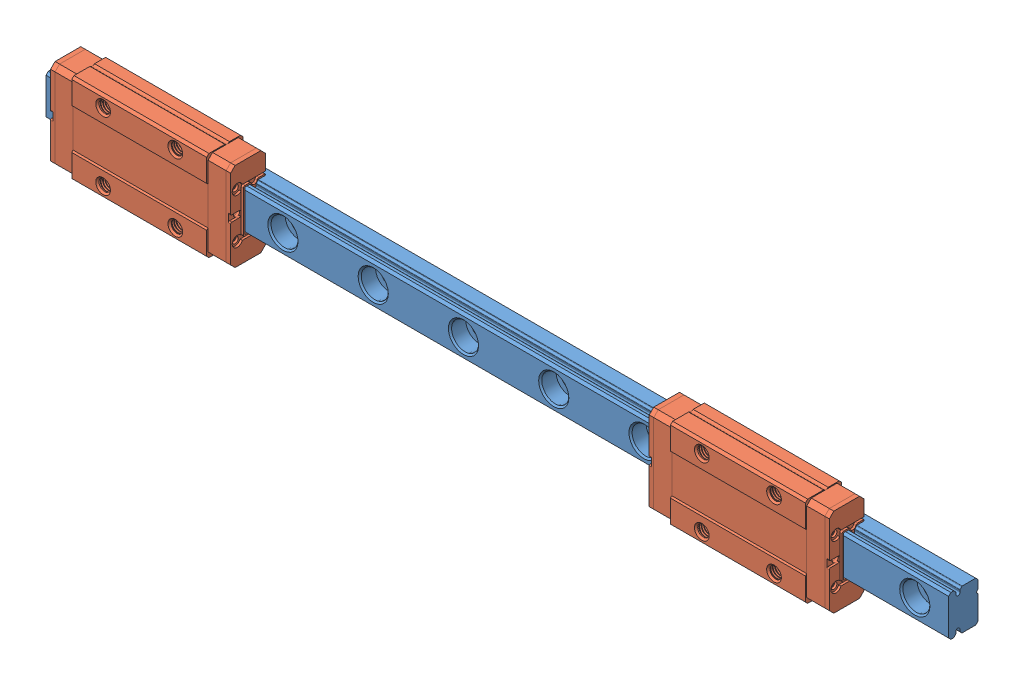
SolidWorks assembly HIWIN_MGN9H_together, configuration two_sliders. Lengths in mm.
Overall size (200 20 10.11).
3 component instances, 2 part files, 7 mates.
Components (placement in the parent):
- Schiene_HIWIN_MGN9H-1: Schiene_HIWIN_MGN9H [Standard] at origin
- slider_HIWIN_MGN9H-1: slider_HIWIN_MGN9H [Standard] at (256.8127 -14.5 1.96)
- slider_HIWIN_MGN9H-2: slider_HIWIN_MGN9H [Standard] at (124.1657 -14.5 1.96)
Mates (geometry in assembly coordinates):
- Deckungsgleich1: coordinate: point of Schiene_HIWIN_MGN9H-1
- Breite1: width anti-aligned: plane of Schiene_HIWIN_MGN9H-1 through (0 0 0.5) normal (0 1 0); plane of Schiene_HIWIN_MGN9H-1 through (0 -9 3.5015) normal (0 -1 0); plane of slider_HIWIN_MGN9H-1 through (256.8127 -14.5 1.96) normal (0 -1 0); plane of slider_HIWIN_MGN9H-1 through (286.7127 5.5 1.96) normal (0 1 0)
- Deckungsgleich2: coincident anti-aligned: plane of Schiene_HIWIN_MGN9H-1 through (0 -0.5 6.5) normal (0 0 1); plane of slider_HIWIN_MGN9H-1 through (286.7127 0 6.5) normal (0 0 -1)
- LimitAbstand1: limit distance = 136.8127 mm aligned: plane of Schiene_HIWIN_MGN9H-1 through (115 -4.5 3.25) normal (-1 0 0); plane of slider_HIWIN_MGN9H-1 through (251.8127 0.6959 5.81) normal (-1 0 0)
- Breite2: width anti-aligned: plane of slider_HIWIN_MGN9H-2 through (124.1657 -14.5 1.96) normal (0 -1 0); plane of slider_HIWIN_MGN9H-2 through (154.0657 5.5 1.96) normal (0 1 0); plane of Schiene_HIWIN_MGN9H-1 through (0 0 0.5) normal (0 1 0); plane of Schiene_HIWIN_MGN9H-1 through (0 -9 3.5015) normal (0 -1 0)
- LimitAbstand2: limit distance = 4.1657 mm aligned: plane of slider_HIWIN_MGN9H-2 through (119.1657 0.6959 5.81) normal (-1 0 0); plane of Schiene_HIWIN_MGN9H-1 through (115 -4.5 3.25) normal (-1 0 0)
- Deckungsgleich3: coincident aligned: plane of slider_HIWIN_MGN9H-1 through (271.7627 -4.5 9.66) normal (0 0 1); plane of slider_HIWIN_MGN9H-2 through (139.1157 -4.5 9.66) normal (0 0 1)
